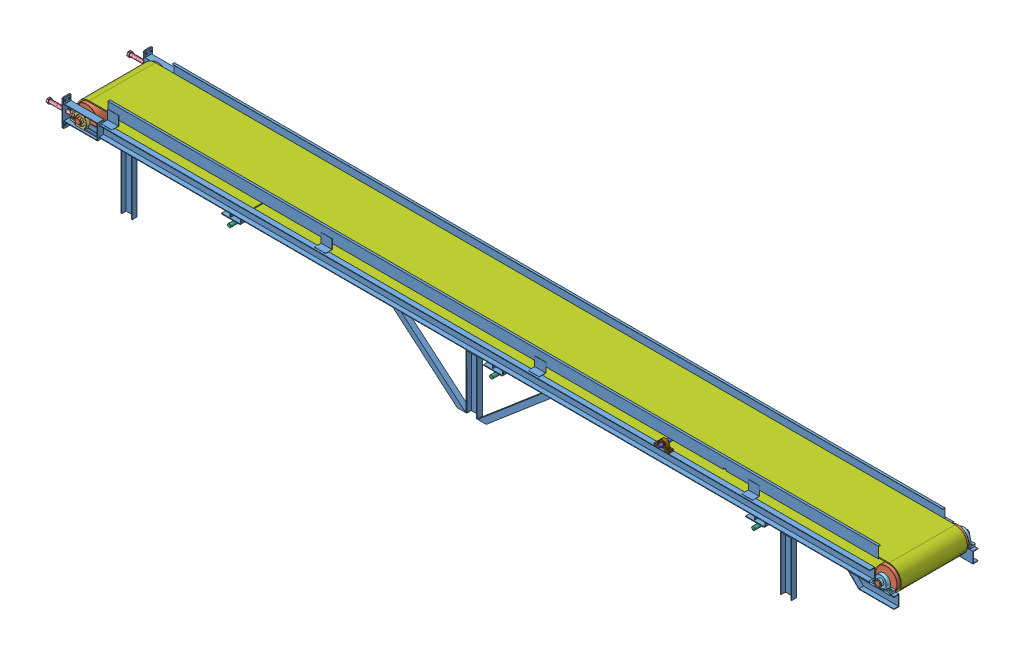
SolidWorks assembly nastrodx, configuration Default. Lengths in mm.
Overall size (7852.77 2195.2 815.72).
16 component instances, 9 part files, 38 mates.
Components (placement in the parent):
- C-channel -b-up-2: C-channel -b-up [Default<As Machined>] at (4036.4781 3775.6231 338.4141) x (0.000207 -1 -0.000382) z (-1 -0.000206 -0.000489) size (1248 810 7547.03)
- roller-belt-Motor-up-1: roller-belt-Motor-up [Default] at (7631.6404 3780.4929 5.1727) x (0.000489 0.000382 -1) z (1 0 0.000489) size (812 200 200)
- Uct 209-up-1: Uct 209-up [Default] at (366.4634 3774.8539 367.6204) x (1 0.000206 0.000489) z (-0.000489 -0.000382 1) size (144 117 54.7)
- Extender-screw-up-1: Extender-screw-up [Default] at (302.9634 3774.8408 367.5894) x (0.000489 0 -1) z (-1 -0.000206 -0.000489) size (46.02 42.15 250)
- Bearing-b_P209_45-up-1: Bearing-b_P209_45-up [Default] at (7631.4747 3726.3547 367.152) x (1 0.000206 0.000489) z (-0.000489 -0.000382 1) size (190 108 62)
- upper-roller-inside-up-1: upper-roller-inside-up [Default] at (6502.8061 3649.373 4.571) x (1 0 0.000489) z (-0.000489 -0.000382 1) size (50 50 810)
- Bearing-b_P209_45-up-2: Bearing-b_P209_45-up [Default] at (7631.8285 3726.6312 -356.8478) x (-1 -0.000206 -0.000489) z (0.000489 0.000382 -1) size (190 108 62)
- Uct 209-up-2: Uct 209-up [Default] at (366.8211 3775.1334 -364.3794) x (1 0.000206 0.000489) z (0.000489 0.000382 -1) size (144 117 54.7)
- Extender-screw-up-2: Extender-screw-up [Default] at (303.3211 3775.1203 -364.4105) x (0.000489 0.000764 -1) z (-1 -0.000206 -0.000489) size (46.02 42.15 250)
- upper-roller-inside-up-2: upper-roller-inside-up [Default] at (4122.8064 3648.8818 3.4078) x (1 0 0.000489) z (-0.000489 -0.000382 1) size (50 50 810)
- upper-roller-inside-up-3: upper-roller-inside-up [Default] at (1742.8067 3648.3906 2.2446) x (1 0 0.000489) z (-0.000489 -0.000382 1) size (50 50 810)
- Belt-1: Belt [Default] at (4036.6418 3775.751 3.4142) x (-0.000207 1 0.000382) z (0.000489 0.000382 -1) size (228 7489 600)
- roller-upper-2: roller-upper [Default] at (5639.6653 3862.5818 4.2307) x (1 0 0.000489) z (-0.000489 -0.000382 1) size (29 29 810)
- UCP-205-1: UCP-205 [Default] at (5639.4923 3862.4467 358.2306) x (0.000489 0.000382 -1) z (1 0 0.000489) size (38.7 70 140)
- UCP-205-2: UCP-205 [Default] at (5639.8383 3862.717 -349.7693) x (0.000489 0.000382 -1) z (1 0.000206 0.000489) size (38.7 70 140)
- roller-belt-Motor-up-2: roller-belt-Motor-up [Default] at (366.6414 3778.9936 1.622) x (0.000489 0.000382 -1) z (1 0 0.000489) size (812 200 200)
Mates (geometry in assembly coordinates):
- Coincident1: coincident: plane of C-channel -b-up-2 through (4036.6418 3775.751 3.4142) normal (0.000489 0.000382 -1)
- Concentric1: concentric anti-aligned: cylinder of C-channel -b-up-2 through (456.8006 3775.1359 -322.3355) axis (0.000489 0.000382 -1) radius 25; cylinder of roller-belt-Motor-up -lower-1 through (956.8425 3775.2719 -408.0911) axis (-0.000489 -0.000382 1) radius 22.5
- Width1: width anti-aligned: plane of C-channel -b-up-2 through (536.7956 3825.1566 -333.2773) normal (-0.000489 -0.000382 1); plane of roller-belt-Motor-up -lower-1 through (536.4682 3824.9008 336.7226) normal (0.000489 0.000382 -1); plane of C-channel -b-up-2 through (956.801 3775.2395 -323.0911) normal (0.000489 0.000382 -1); plane of roller-belt-Motor-up -lower-1 through (956.4834 3774.9913 326.9088) normal (-0.000489 -0.000382 1)
- Concentric2: concentric anti-aligned: cylinder of roller-belt-Motor-up -lower-1 through (956.8425 3775.2719 -408.0911) axis (-0.000489 -0.000382 1) radius 22.5; cylinder of Uct 209-up-1 through (366.4487 3774.8424 397.8204) axis (0.000489 0.000382 -1) radius 22.5
- Coincident2: coincident anti-aligned: plane of C-channel -b-up-2 through (310.4461 3839.8393 375.6179) normal (-0.000489 -0.000382 1); plane of Uct 209-up-1 through (415.9474 3833.361 375.6669) normal (0.000489 0.000382 -1)
- Parallel1: parallel anti-aligned: plane of C-channel -b-up-2 through (310.4488 3826.8393 375.6129) normal (0.000207 -1 -0.000382); plane of Uct 209-up-1 through (415.9568 3825.8672 359.6641) normal (-0.000207 1 0.000382)
- Concentric3: concentric aligned: cylinder of Uct 209-up-1 through (279.4634 3774.8359 367.5779) axis (1 0.000206 0.000489) radius 14.5; cylinder of Extender-screw-up-1 through (62.4635 3774.7911 367.4718) axis (1 0.000206 0.000489) radius 14.5
- Coincident3: coincident anti-aligned: plane of Uct 209-up-1 through (295.4697 3793.1774 347.0927) normal (1 0.000206 0.000489); plane of Extender-screw-up-1 through (295.4634 3774.8392 367.5857) normal (-1 -0.000206 -0.000489)
- Coincident4: coincident anti-aligned: plane of C-channel -b-up-2 through (7436.5192 3726.3248 340.0568) normal (-0.000207 1 0.000382); plane of Bearing-b_P209_45-up-1 through (7536.4615 3726.3248 394.1056) normal (0.000207 -1 -0.000382)
- Coincident5: coincident aligned: plane of C-channel -b-up-2 through (4036.4781 3775.6231 338.4141) normal (0.000489 0.000382 -1); plane of Bearing-b_P209_45-up-1 through (7631.4879 3726.365 340.152) normal (0.000489 0.000382 -1)
- Concentric4: concentric aligned: cylinder of Bearing-b_P209_45-up-1 through (7631.5036 3780.386 285.1727) axis (-0.000489 -0.000382 1) radius 22.5; cylinder of roller-belt-Motor-up-1 through (7631.8388 3780.648 -400.8272) axis (-0.000489 -0.000382 1) radius 22.5
- Coincident6: coincident anti-aligned: plane of C-channel -b-up-2 through (-723.5039 3690.6538 336.0556) normal (0.000207 -1 -0.000382); plane of UCP206-3 through (1710.6085 3691.1361 389.7453) normal (-0.000207 1 0.000382)
- Width4: width aligned: plane of C-channel -b-up-2 through (1657.6337 3691.1448 338.2194) normal (-1 -0.000206 -0.000489); plane of UCP206-3 through (1827.6337 3691.1799 338.3025) normal (1 0.000206 0.000489); plane of C-channel -b-up-2 through (1660.11 3691.1268 386.7206) normal (-1 -0.000206 -0.000489); plane of UCP206-3 through (1825.1305 3691.1769 344.8013) normal (1 0.000206 0.000489)
- Width5: width anti-aligned: plane of UCP206-3 through (1777.632 3691.1682 341.7781) normal (0.000489 0.000382 -1); plane of C-channel -b-up-2 through (1822.1085 3691.1591 389.7998) normal (-0.000489 -0.000382 1); plane of UCP206-3 through (1827.6068 3691.1589 393.3025) normal (-0.000489 -0.000382 1); plane of C-channel -b-up-2 through (1827.6337 3691.1799 338.3025) normal (0.000489 0.000382 -1)
- Coincident8: coincident anti-aligned: plane of C-channel -b-up-2 through (1656.4957 3691.145 337.2188) normal (0.000207 -1 -0.000382); plane of UCP206-1 through (4090.6082 3691.6273 390.9085) normal (-0.000207 1 0.000382)
- Width6: width anti-aligned: plane of UCP206-1 through (4040.1097 3691.618 387.8838) normal (-1 -0.000206 -0.000489); plane of C-channel -b-up-2 through (4205.1302 3691.6681 345.9645) normal (1 0.000206 0.000489); plane of UCP206-1 through (4207.6333 3691.6711 339.4657) normal (1 0.000206 0.000489); plane of C-channel -b-up-2 through (4037.6334 3691.636 339.3826) normal (-1 -0.000206 -0.000489)
- Width7: width anti-aligned: plane of UCP206-1 through (4087.6082 3691.6266 390.907) normal (-0.000489 -0.000382 1); plane of C-channel -b-up-2 through (4043.1316 3691.6358 342.8853) normal (0.000489 0.000382 -1); plane of UCP206-1 through (4207.6333 3691.6711 339.4657) normal (0.000489 0.000382 -1); plane of C-channel -b-up-2 through (4207.6065 3691.6501 394.4657) normal (-0.000489 -0.000382 1)
- Coincident9: coincident anti-aligned: plane of C-channel -b-up-2 through (4036.4954 3691.6361 338.3821) normal (0.000207 -1 -0.000382); plane of UCP206-2 through (6470.6078 3692.1184 392.0717) normal (-0.000207 1 0.000382)
- Width8: width anti-aligned: plane of C-channel -b-up-2 through (6587.6061 3692.1412 395.6289) normal (-0.000489 -0.000382 1); plane of UCP206-2 through (6587.633 3692.1622 340.6289) normal (0.000489 0.000382 -1); plane of C-channel -b-up-2 through (6423.1313 3692.127 344.0485) normal (0.000489 0.000382 -1); plane of UCP206-2 through (6467.6078 3692.1178 392.0702) normal (-0.000489 -0.000382 1)
- Width9: width anti-aligned: plane of C-channel -b-up-2 through (6417.633 3692.1272 340.5458) normal (-1 -0.000206 -0.000489); plane of UCP206-2 through (6587.633 3692.1622 340.6289) normal (1 0.000206 0.000489); plane of C-channel -b-up-2 through (6585.1298 3692.1592 347.1277) normal (1 0.000206 0.000489); plane of UCP206-2 through (6420.1093 3692.1092 389.047) normal (-1 -0.000206 -0.000489)
- Concentric5: concentric anti-aligned: cylinder of upper-roller-inside-up-1 through (6502.6082 3649.2184 409.571) axis (0.000489 0.000382 -1) radius 15; cylinder of UCP206-2 through (6502.6358 3649.24 352.933) axis (-0.000489 -0.000382 1) radius 15
- Concentric6: concentric anti-aligned: cylinder of UCP206-1 through (4122.6362 3648.7488 351.7698) axis (-0.000489 -0.000382 1) radius 15; cylinder of upper-roller-inside-up-2 through (4122.6085 3648.7272 408.4078) axis (0.000489 0.000382 -1) radius 15
- Concentric7: concentric anti-aligned: cylinder of UCP206-3 through (1742.6365 3648.2576 350.6066) axis (-0.000489 -0.000382 1) radius 15; cylinder of upper-roller-inside-up-3 through (1742.6088 3648.236 407.2446) axis (0.000489 0.000382 -1) radius 15
- Width12: width anti-aligned: plane of upper-roller-inside-up-3 through (1742.6088 3648.236 407.2446) normal (-0.000489 -0.000382 1); plane of C-channel -b-up-2 through (1743.0046 3648.5453 -402.7553) normal (0.000489 0.000382 -1); plane of upper-roller-inside-up-3 through (536.4682 3824.9008 336.7226) normal (0.000489 0.000382 -1); plane of C-channel -b-up-2 through (536.7956 3825.1566 -333.2773) normal (-0.000489 -0.000382 1)
- InPlace1: in place: plane of ? through (4036.6525 3723.6228 3.3943) normal (0.000489 0.000382 -1); plane of ? through (4036.6525 3723.6228 3.3943) normal (0.000489 0.000382 -1); moOrthogonalPlaneRef_w of ? through (4036.6525 3723.6228 3.3943) normal (0.000489 0.000382 -1); plane of ? through (4036.6525 3723.6228 3.3943) normal (1 0.000206 0.000489); plane of ? through (4036.6525 3723.6228 3.3943) normal (0.000489 0.000382 -1); plane of ? through (4036.6525 3723.6228 3.3943) normal (-0.000207 1 0.000382); plane of C-channel -b-up-2 through (4036.6418 3775.751 3.4142) normal (0.000489 0.000382 -1); unknown of Belt-1
- Coincident13: coincident aligned: plane of ?; plane of ?
- Coincident14: coincident aligned: moOrthogonalPlaneRef_w of C-channel -b-up-2; plane of Belt-1 through (4036.6418 3775.751 3.4142) normal (1 0.000206 0.000489)
- Coincident15: coincident anti-aligned: moOrthogonalPlaneRef_w of C-channel -b-up-2; plane of Belt-1 through (4036.6418 3775.751 3.4142) normal (-0.000207 1 0.000382)
- Concentric11: concentric anti-aligned: cylinder of roller-upper-2 through (5639.4674 3862.4272 409.2306) axis (0.000489 0.000382 -1) radius 12.5; cylinder of UCP-205-1 through (5639.4853 3862.4412 372.5306) axis (-0.000489 -0.000382 1) radius 12.5
- Coincident24: coincident aligned: plane of C-channel -b-up-2 through (536.4682 3824.9008 336.7226) normal (0.000489 0.000382 -1); plane of UCP-205-1 through (5571.1016 3838.7539 339.1881) normal (0.000489 0.000382 -1)
- Concentric12: concentric aligned: cylinder of roller-upper-2 through (5639.8632 3862.7365 -400.7693) axis (-0.000489 -0.000382 1) radius 12.5; cylinder of UCP-205-2 through (5639.8313 3862.7115 -335.4693) axis (-0.000489 -0.000382 1) radius 12.5
- Coincident25: coincident anti-aligned: plane of C-channel -b-up-2 through (536.7956 3825.1566 -333.2773) normal (-0.000207 1 0.000382); plane of UCP-205-2 through (5709.8551 3826.2387 -368.749) normal (0.000207 -1 -0.000382)
- Coincident26: coincident aligned: plane of C-channel -b-up-2 through (536.7956 3825.1566 -333.2773) normal (-0.000489 -0.000382 1); plane of UCP-205-2 through (5571.4339 3838.9956 -330.8117) normal (-0.000489 -0.000382 1)
- Coincident28: coincident anti-aligned: plane of roller-belt-Motor-up -lower-1 through (956.8425 3775.2719 -408.0911) normal (0.000489 0.000382 -1); plane of Gear_motor-b-up-1 through (972.9459 3759.1753 -408.0893) normal (-0.000489 -0.000382 1)
- Concentric14: concentric anti-aligned: circle of roller-belt-Motor-up -lower-1; cylinder of Gear_motor-b-up-1 through (956.8767 3775.2987 -478.0911) axis (-0.000489 -0.000382 1) radius 17.5
- Parallel2: parallel aligned: plane of C-channel -b-up-2 through (536.8163 3725.1566 -333.3154) normal (0.000207 -1 -0.000382); plane of Gear_motor-b-up-1 through (1248.8044 3664.8321 -669.7906) normal (0.000207 -1 -0.000382)
- Coincidente1: coincident anti-aligned: plane of C-channel -b-up-2 through (7536.4776 3776.3454 340.1247) normal (1 0.000206 0.000489); plane of Bearing-b_P209_45-up-1 through (7536.4578 3744.3248 394.1125) normal (-1 -0.000206 -0.000489)
- Concentrico1: concentric anti-aligned: cylinder of Uct 209-up-1 through (366.4487 3774.8424 397.8204) axis (0.000489 0.000382 -1) radius 22.5; cylinder of Belt-1 through (366.7889 3775.1082 -298.3794) axis (-0.000489 -0.000382 1) radius 114
